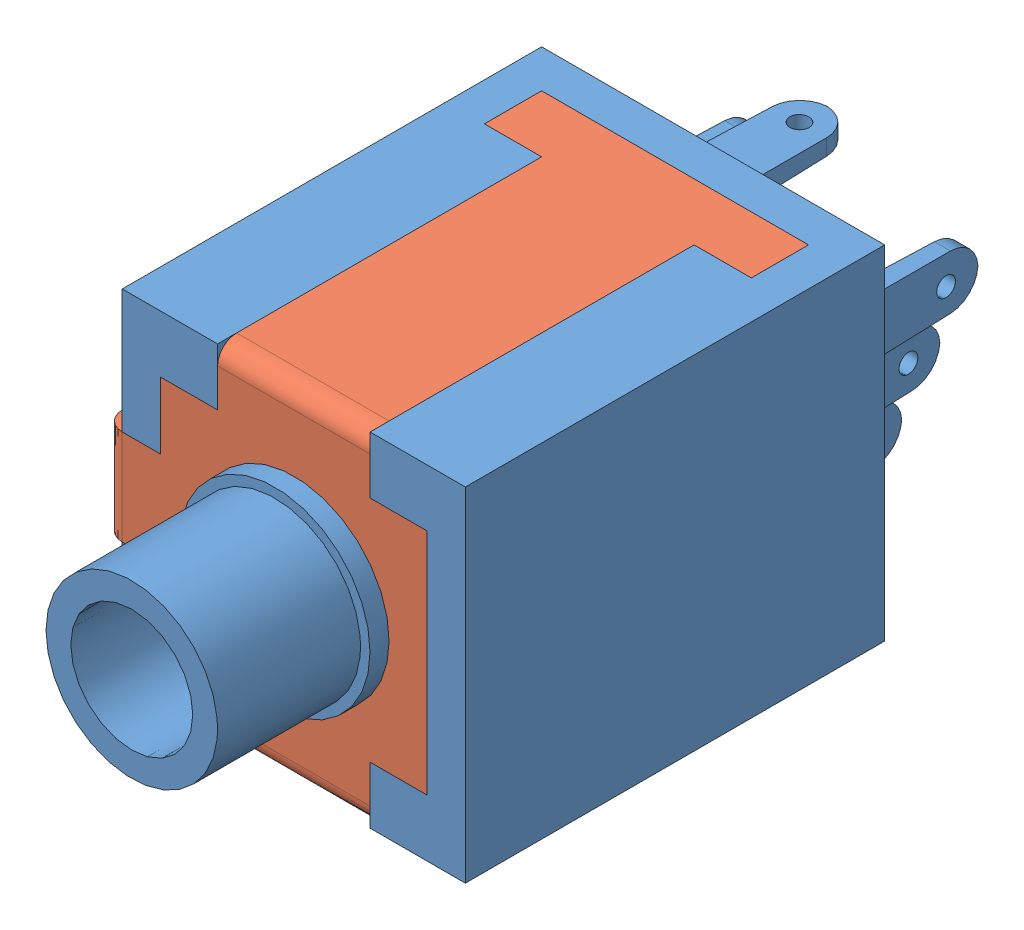
SolidWorks assembly 6.35mm jack, configuration Default. Lengths in mm.
Overall size (19 18 36.5).
2 component instances, 2 part files, 5 mates.
Components (placement in the parent):
- 6.35mm jack-1: 6.35mm jack [Default] at origin size (18 18 36.5)
- Gnd Plate_6.35mm jack-1: Gnd Plate_6.35mm jack [Default] at (0 0 10) size (17 18 20)
Mates (geometry in assembly coordinates):
- Coincident1: coordinate: point of 6.35mm jack-1; point of assembly
- InPlace1: in place: plane of 6.35mm jack-1 through (0 0 10) normal (0 0 1); plane of Gnd Plate_6.35mm jack-1 through (0 0 10) normal (0 0 1); moOrthogonalPlaneRef_w of 6.35mm jack-1 through (0 0 10) normal (0 0 1); plane of Gnd Plate_6.35mm jack-1 through (0 0 10) normal (0 1 0); plane of 6.35mm jack-1 through (0 0 10) normal (0 0 1); plane of Gnd Plate_6.35mm jack-1 through (0 0 10) normal (1 0 0); plane of 6.35mm jack-1 through (0 0 10) normal (0 0 1); unknown of Gnd Plate_6.35mm jack-1
- Coincident2: coincident aligned: plane of 6.35mm jack-1; plane of Gnd Plate_6.35mm jack-1
- Coincident3: coincident aligned: moOrthogonalPlaneRef_w of 6.35mm jack-1 through (0 0 10) normal (0 1 0); plane of Gnd Plate_6.35mm jack-1 through (0 0 10) normal (0 1 0)
- Coincident4: coincident anti-aligned: moOrthogonalPlaneRef_w of 6.35mm jack-1 through (0 0 10) normal (-1 0 0); plane of Gnd Plate_6.35mm jack-1 through (0 0 10) normal (1 0 0)
